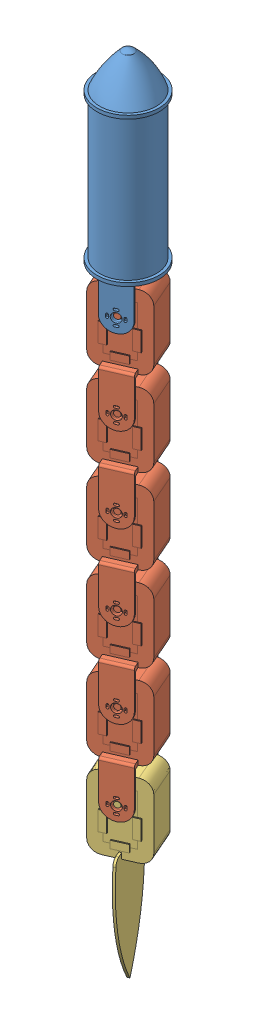
SolidWorks assembly large_tail_eel, configuration 預設. Lengths in mm.
Overall size (61.21 711.18 63.77).
7 component instances, 3 part files, 19 mates.
Components (placement in the parent):
- base_link-1: base_link [預設] at (-66.5632 -1.1579 104.9753) size (55 204.98 55)
- link2-1: link2 [預設] at (-45.8446 -161.6209 204.2877) x (0 1 0) z (0.399282 0 0.916828) size (107 45 40.5)
- link2-2: link2 [預設] at (-45.8446 -236.3209 204.2877) x (0 1 0) z (0.399282 0 0.916828) size (107 45 40.5)
- link2-3: link2 [預設] at (-45.8446 -311.0209 204.2877) x (0 1 0) z (0.399282 0 0.916828) size (107 45 40.5)
- link2-4: link2 [預設] at (-45.8446 -385.7209 204.2877) x (0 1 0) z (0.399282 0 0.916828) size (107 45 40.5)
- link2-5: link2 [預設] at (-45.8446 -460.4209 204.2877) x (0 1 0) z (0.399282 0 0.916828) size (107 45 40.5)
- large_eel-2: large_eel [預設] at (-115.6308 -494.9991 54.7116) x (0 1 0) z (0.399282 0 0.916828) size (165 45 49.96)
Mates (geometry in assembly coordinates):
- 同軸心1: concentric aligned: cylinder of base_link-1 through (-52.4327 -86.9209 189.16) axis (-0.399282 0 -0.916828) radius 2.7; cylinder of link2-1 through (-51.4345 -86.9209 191.4521) axis (-0.399282 0 -0.916828) radius 2.5
- 平行1: parallel aligned: plane of base_link-1 through (-42.6286 -56.9209 181.6182) normal (0.916828 0 -0.399282); plane of link2-1 through (-19.626 -131.6209 208.1394) normal (0.916828 0 -0.399282)
- 重合/共線/共點1: coincident aligned: circle of base_link-1; plane of link2-1 through (-38.2582 -86.9209 221.7074) normal (0.399282 0 0.916828)
- 重合/共線/共點2: coincident aligned: plane of link2-1 through (-60.8832 -131.6209 226.1071) normal (-0.916828 0 0.399282); plane of link2-2 through (-60.8832 -206.3209 226.1071) normal (-0.916828 0 0.399282)
- 同軸心2: concentric anti-aligned: cylinder of link2-1 through (-53.8302 -161.6209 185.9511) axis (0.399282 0 0.916828) radius 3.7; cylinder of link2-2 through (-51.4345 -161.6209 191.4521) axis (-0.399282 0 -0.916828) radius 2.5
- 平行2: parallel aligned: plane of link2-1 through (-54.7929 -154.5209 186.3704) normal (0 -1 0); plane of link2-2 through (-54.7929 -229.2209 186.3704) normal (0 -1 0)
- 重合/共線/共點4: coincident aligned: plane of link2-1 through (-51.4345 -71.6862 191.4521) normal (-0.399282 0 -0.916828); plane of link2-2 through (-51.4345 -146.3862 191.4521) normal (-0.399282 0 -0.916828)
- 重合/共線/共點5: coincident aligned: plane of link2-2 through (-60.8832 -206.3209 226.1071) normal (-0.916828 0 0.399282); plane of link2-3 through (-60.8832 -281.0209 226.1071) normal (-0.916828 0 0.399282)
- 同軸心3: concentric anti-aligned: cylinder of link2-2 through (-53.8302 -236.3209 185.9511) axis (0.399282 0 0.916828) radius 3.7; cylinder of link2-3 through (-51.4345 -236.3209 191.4521) axis (-0.399282 0 -0.916828) radius 2.5
- 重合/共線/共點6: coincident aligned: plane of link2-2 through (-53.8302 -146.3862 185.9511) normal (-0.399282 0 -0.916828); plane of link2-3 through (-53.8302 -221.0862 185.9511) normal (-0.399282 0 -0.916828)
- 重合/共線/共點7: coincident aligned: plane of link2-3 through (-60.8832 -281.0209 226.1071) normal (-0.916828 0 0.399282); plane of link2-4 through (-60.8832 -355.7209 226.1071) normal (-0.916828 0 0.399282)
- 同軸心4: concentric anti-aligned: cylinder of link2-3 through (-53.8302 -311.0209 185.9511) axis (0.399282 0 0.916828) radius 3.7; cylinder of link2-4 through (-51.4345 -311.0209 191.4521) axis (-0.399282 0 -0.916828) radius 2.5
- 重合/共線/共點8: coincident aligned: plane of link2-3 through (-51.4345 -221.0862 191.4521) normal (-0.399282 0 -0.916828); plane of link2-4 through (-51.4345 -295.7862 191.4521) normal (-0.399282 0 -0.916828)
- 重合/共線/共點10: coincident aligned: plane of link2-4 through (-51.4345 -295.7862 191.4521) normal (-0.399282 0 -0.916828); plane of link2-5 through (-51.4345 -370.4862 191.4521) normal (-0.399282 0 -0.916828)
- 重合/共線/共點11: coincident aligned: plane of link2-4 through (-60.8832 -355.7209 226.1071) normal (-0.916828 0 0.399282); plane of link2-5 through (-60.8832 -430.4209 226.1071) normal (-0.916828 0 0.399282)
- 同軸心6: concentric anti-aligned: cylinder of link2-4 through (-53.8302 -385.7209 185.9511) axis (0.399282 0 0.916828) radius 3.7; cylinder of link2-5 through (-51.4345 -385.7209 191.4521) axis (-0.399282 0 -0.916828) radius 2.5
- 重合/共線/共點14: coincident aligned: plane of link2-5 through (-60.8832 -430.4209 226.1071) normal (-0.916828 0 0.399282); plane of large_eel-2 through (-60.8832 -505.1209 226.1071) normal (-0.916828 0 0.399282)
- 重合/共線/共點15: coincident aligned: plane of link2-5 through (-51.4345 -370.4862 191.4521) normal (-0.399282 0 -0.916828); plane of large_eel-2 through (-51.4345 -445.1862 191.4521) normal (-0.399282 0 -0.916828)
- 同軸心8: concentric anti-aligned: cylinder of link2-5 through (-53.8302 -460.4209 185.9511) axis (0.399282 0 0.916828) radius 3.7; cylinder of large_eel-2 through (-51.4345 -460.4209 191.4521) axis (-0.399282 0 -0.916828) radius 2.5
